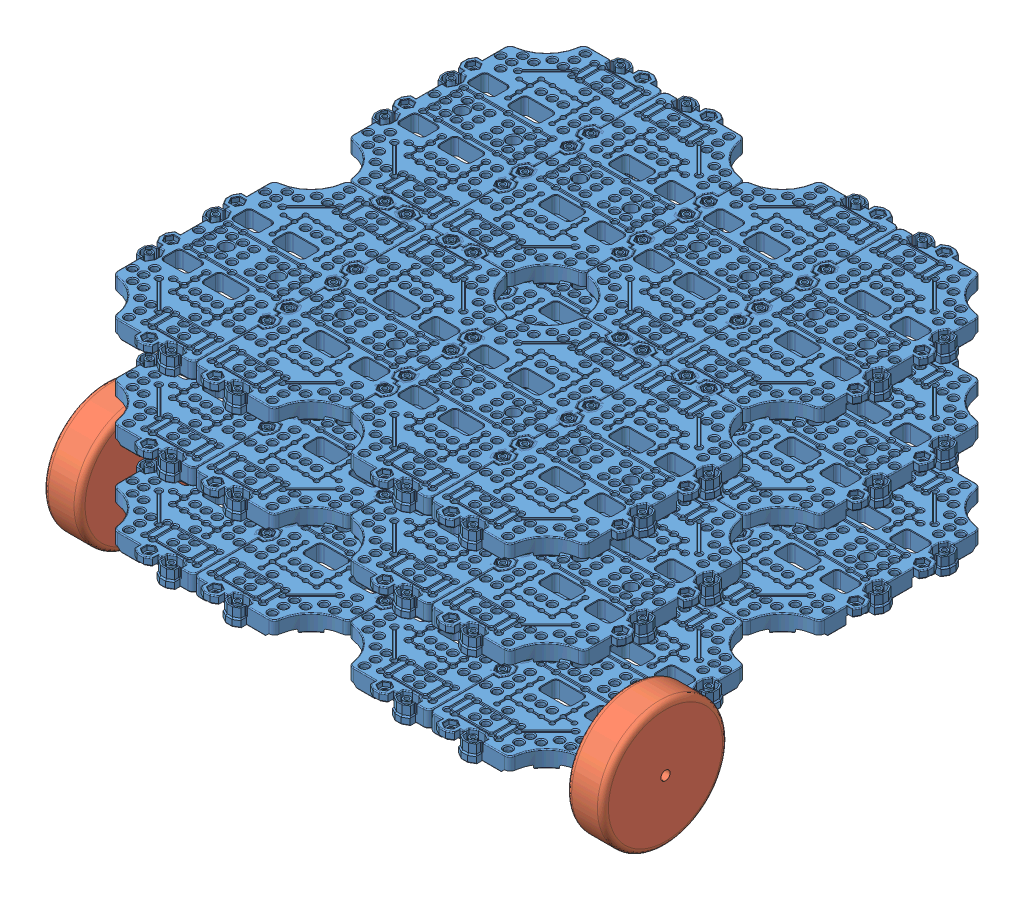
SolidWorks assembly minibot, configuration 預設. Lengths in mm.
Overall size (406.02 141 366.75).
36 component instances, 3 part files, 4 mates.
Components (placement in the parent):
- 組合件4^minibot-1: 組合件4^minibot [預設] at origin size (348.29 9.85 366.75) (virtual)
  - 複製 of 組合件3^組合件4_minibot-1: 複製 of 組合件3^組合件4_minibot [預設] at (61.6154 0 -10.7198) size (265.55 9.85 137.55) (virtual)
    - waffle_plate - P-BP-A001_3D-1: waffle_plate - P-BP-A001_3D [Default] at (41.4794 2.9137 137.552) x (-1 0 0) z (0 0 -1) size (73.55 9.85 137.55)
    - waffle_plate - P-BP-A001_3D-2: waffle_plate - P-BP-A001_3D [Default] at (-86.5206 2.9137 137.552) size (73.55 9.85 137.55)
    - waffle_plate - P-BP-A001_3D-3: waffle_plate - P-BP-A001_3D [Default] at (-86.5206 2.9137 137.552) x (-1 0 0) z (0 0 -1) size (73.55 9.85 137.55)
    - waffle_plate - P-BP-A001_3D-4: waffle_plate - P-BP-A001_3D [Default] at (41.4794 2.9137 137.552) size (73.55 9.85 137.55)
  - 複製 of 組合件2^組合件4_minibot-1: 複製 of 組合件2^組合件4_minibot [預設] at (91.7846 0 -70.2364) x (0.907561 0 0.41992) z (-0.41992 0 0.907561) size (298.77 9.85 236.35) (virtual)
    - waffle_plate - P-BP-A001_3D-1: waffle_plate - P-BP-A001_3D [Default] at (146.7675 2.9137 290.2703) x (0.907561 0 -0.41992) z (0.41992 0 0.907561) size (73.55 9.85 137.55)
    - waffle_plate - P-BP-A001_3D-2: waffle_plate - P-BP-A001_3D [Default] at (30.5997 2.9137 344.02) x (-0.907561 0 0.41992) z (-0.41992 0 -0.907561) size (73.55 9.85 137.55)
    - waffle_plate - P-BP-A001_3D-3: waffle_plate - P-BP-A001_3D [Default] at (30.5997 2.9137 344.02) x (0.907561 0 -0.41992) z (0.41992 0 0.907561) size (73.55 9.85 137.55)
    - waffle_plate - P-BP-A001_3D-4: waffle_plate - P-BP-A001_3D [Default] at (146.7675 2.9137 290.2703) x (-0.907561 0 0.41992) z (-0.41992 0 -0.907561) size (73.55 9.85 137.55)
- 組合件4^minibot-2: 組合件4^minibot [預設] at (0 50 0) size (348.29 9.85 366.75) (virtual)
  - 複製 of 組合件3^組合件4_minibot-1: 複製 of 組合件3^組合件4_minibot [預設] at (61.6154 0 -10.7198) size (265.55 9.85 137.55) (virtual)
    - waffle_plate - P-BP-A001_3D-1: waffle_plate - P-BP-A001_3D [Default] at (41.4794 2.9137 137.552) x (-1 0 0) z (0 0 -1) size (73.55 9.85 137.55)
    - waffle_plate - P-BP-A001_3D-2: waffle_plate - P-BP-A001_3D [Default] at (-86.5206 2.9137 137.552) size (73.55 9.85 137.55)
    - waffle_plate - P-BP-A001_3D-3: waffle_plate - P-BP-A001_3D [Default] at (-86.5206 2.9137 137.552) x (-1 0 0) z (0 0 -1) size (73.55 9.85 137.55)
    - waffle_plate - P-BP-A001_3D-4: waffle_plate - P-BP-A001_3D [Default] at (41.4794 2.9137 137.552) size (73.55 9.85 137.55)
  - 複製 of 組合件2^組合件4_minibot-1: 複製 of 組合件2^組合件4_minibot [預設] at (91.7846 0 -70.2364) x (0.907561 0 0.41992) z (-0.41992 0 0.907561) size (298.77 9.85 236.35) (virtual)
    - waffle_plate - P-BP-A001_3D-1: waffle_plate - P-BP-A001_3D [Default] at (146.7675 2.9137 290.2703) x (0.907561 0 -0.41992) z (0.41992 0 0.907561) size (73.55 9.85 137.55)
    - waffle_plate - P-BP-A001_3D-2: waffle_plate - P-BP-A001_3D [Default] at (30.5997 2.9137 344.02) x (-0.907561 0 0.41992) z (-0.41992 0 -0.907561) size (73.55 9.85 137.55)
    - waffle_plate - P-BP-A001_3D-3: waffle_plate - P-BP-A001_3D [Default] at (30.5997 2.9137 344.02) x (0.907561 0 -0.41992) z (0.41992 0 0.907561) size (73.55 9.85 137.55)
    - waffle_plate - P-BP-A001_3D-4: waffle_plate - P-BP-A001_3D [Default] at (146.7675 2.9137 290.2703) x (-0.907561 0 0.41992) z (-0.41992 0 -0.907561) size (73.55 9.85 137.55)
- 組合件4^minibot-3: 組合件4^minibot [預設] at (0 100 0) size (348.29 9.85 366.75) (virtual)
  - 複製 of 組合件3^組合件4_minibot-1: 複製 of 組合件3^組合件4_minibot [預設] at (61.6154 0 -10.7198) size (265.55 9.85 137.55) (virtual)
    - waffle_plate - P-BP-A001_3D-1: waffle_plate - P-BP-A001_3D [Default] at (41.4794 2.9137 137.552) x (-1 0 0) z (0 0 -1) size (73.55 9.85 137.55)
    - waffle_plate - P-BP-A001_3D-2: waffle_plate - P-BP-A001_3D [Default] at (-86.5206 2.9137 137.552) size (73.55 9.85 137.55)
    - waffle_plate - P-BP-A001_3D-3: waffle_plate - P-BP-A001_3D [Default] at (-86.5206 2.9137 137.552) x (-1 0 0) z (0 0 -1) size (73.55 9.85 137.55)
    - waffle_plate - P-BP-A001_3D-4: waffle_plate - P-BP-A001_3D [Default] at (41.4794 2.9137 137.552) size (73.55 9.85 137.55)
  - 複製 of 組合件2^組合件4_minibot-1: 複製 of 組合件2^組合件4_minibot [預設] at (91.7846 0 -70.2364) x (0.907561 0 0.41992) z (-0.41992 0 0.907561) size (298.77 9.85 236.35) (virtual)
    - waffle_plate - P-BP-A001_3D-1: waffle_plate - P-BP-A001_3D [Default] at (146.7675 2.9137 290.2703) x (0.907561 0 -0.41992) z (0.41992 0 0.907561) size (73.55 9.85 137.55)
    - waffle_plate - P-BP-A001_3D-2: waffle_plate - P-BP-A001_3D [Default] at (30.5997 2.9137 344.02) x (-0.907561 0 0.41992) z (-0.41992 0 -0.907561) size (73.55 9.85 137.55)
    - waffle_plate - P-BP-A001_3D-3: waffle_plate - P-BP-A001_3D [Default] at (30.5997 2.9137 344.02) x (0.907561 0 -0.41992) z (0.41992 0 0.907561) size (73.55 9.85 137.55)
    - waffle_plate - P-BP-A001_3D-4: waffle_plate - P-BP-A001_3D [Default] at (146.7675 2.9137 290.2703) x (-0.907561 0 0.41992) z (-0.41992 0 -0.907561) size (73.55 9.85 137.55)
- wheel-1: wheel [預設] at (-93.0787 -3.3654 278.4654) x (0 1 0) z (0 0 1) size (68 20 68)
- wheel-2: wheel [預設] at (191.2683 -3.3654 278.4654) x (0 1 0) z (0 0 1) size (68 20 68)
- wheel2-1: wheel2 [預設] at (41.5944 -20.6481 105.8292) size (32 32 32)
Mates (geometry in assembly coordinates):
- 重合/共線/共點2: coincident: cylinder of 組合件4^minibot-1/複製 of 組合件2^組合件4_minibot-1/waffle_plate - P-BP-A001_3D-2; cylinder of wheel-1 through (-113.0787 -3.3654 278.4654) axis (1 0 0) radius 2.5
- 重合/共線/共點4: coincident: plane of 組合件4^minibot-1/複製 of 組合件2^組合件4_minibot-1/waffle_plate - P-BP-A001_3D-1 through (171.2683 2.9137 268.4035) normal (1 0 0); plane of wheel-2 through (171.2683 -3.3654 278.4654) normal (-1 0 0)
- 重合/共線/共點5: coincident: plane of 組合件4^minibot-1/複製 of 組合件2^組合件4_minibot-1/waffle_plate - P-BP-A001_3D-2 through (-93.0787 2.9137 277.2609) normal (-1 0 0); plane of wheel-1 through (-93.0787 -3.3654 278.4654) normal (1 0 0)
- 同軸心1: concentric: cylinder of assembly; cylinder of assembly; cylinder of wheel-1 through (-113.0787 -3.3654 278.4654) axis (1 0 0) radius 2.5; cylinder of wheel-2 through (171.2683 -3.3654 278.4654) axis (1 0 0) radius 2.5
